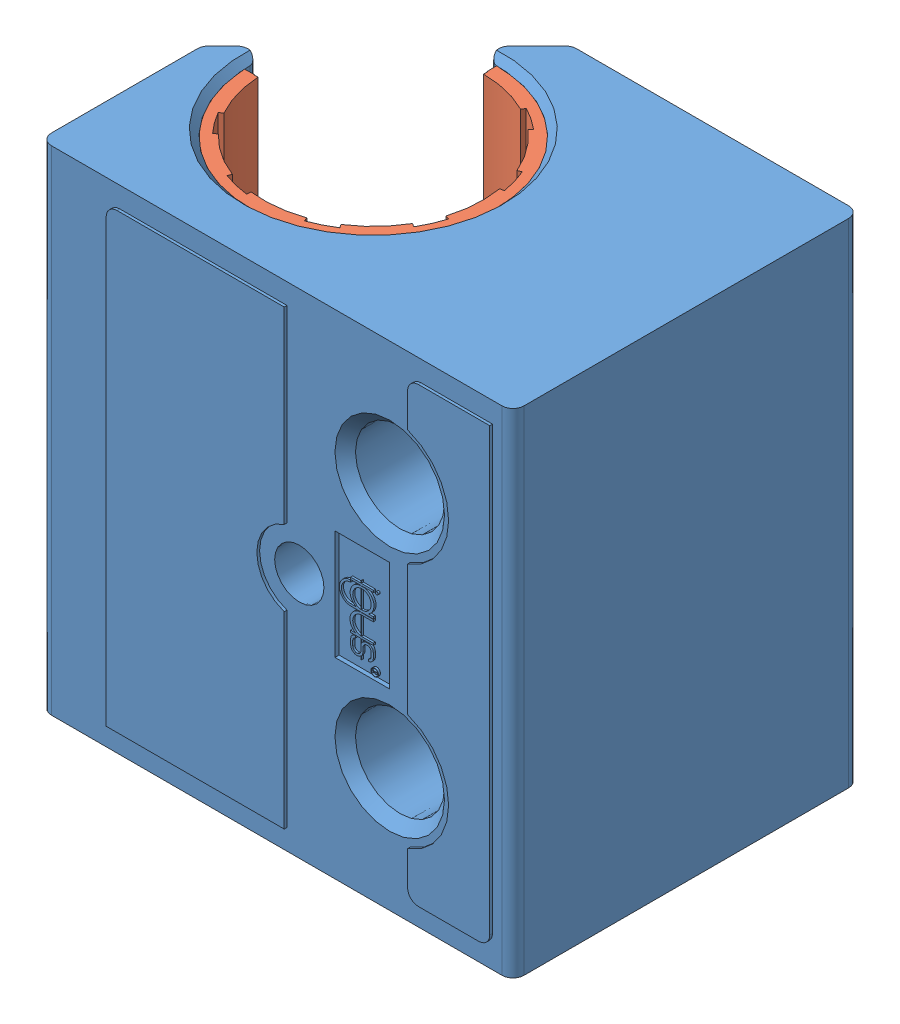
SolidWorks assembly bearing_assembly, configuration Default. Lengths in mm.
Overall size (34.5 36.12 25.5).
2 component instances, 2 part files, 2 mates.
Components (placement in the parent):
- bearing-1: bearing [Default] at (-34.1756 -54.0126 49.0726) size (34.5 36.12 25.5)
- bearing_collar-1: bearing_collar [Default] at (-33.6895 -54.0126 49.728) x (0.99974 0 -0.022785) z (0.022785 0 0.99974) size (19.6 35 19.6)
Mates (geometry in assembly coordinates):
- Coincident1: coincident anti-aligned: circle of bearing-1; circle of bearing_collar-1
- Coincident4: coincident aligned: line of bearing-1 through (-5.1756 26.1864 19.0726) axis (0 -1 0); line of bearing_collar-1 through (-5.1756 45.4864 19.0726) axis (0 -1 0)
